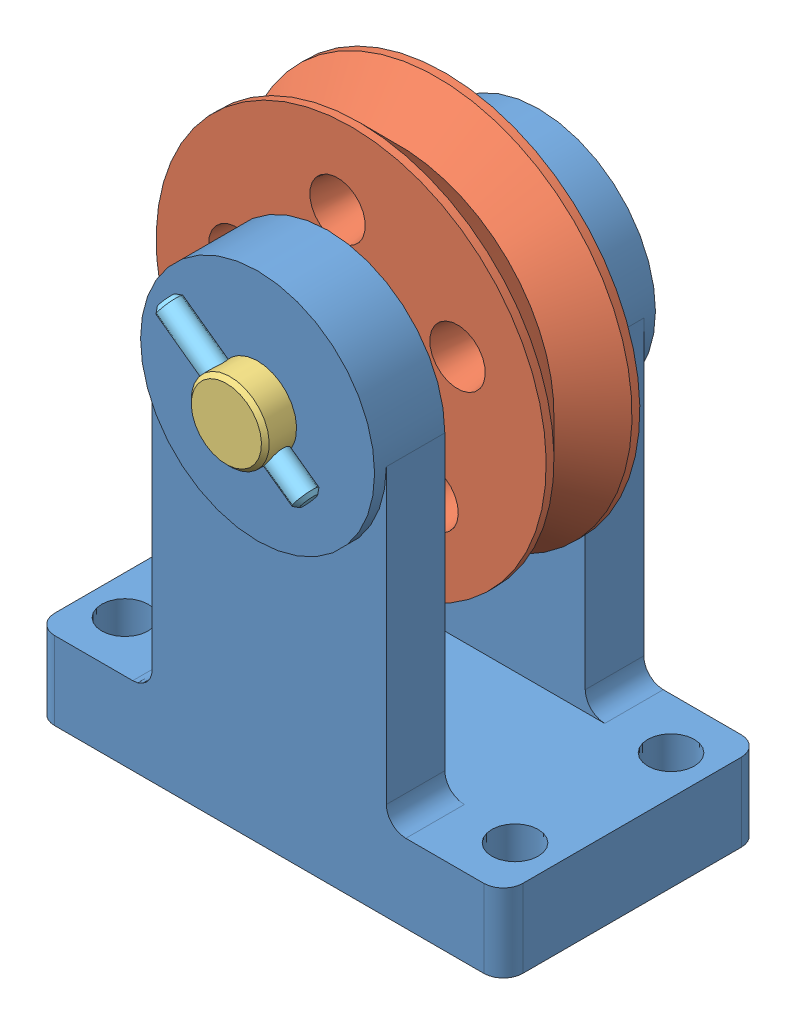
SolidWorks assembly PARCA_BİRLESTIRMESI, configuration Varsayılan. Lengths in mm.
Overall size (136.15 168.07 87).
5 component instances, 5 part files, 8 mates.
Components (placement in the parent):
- kasnak_yeri-1: kasnak_yeri [Default] at (-26.8186 -62.4075 130) size (120 130 72)
- kasnak-1: kasnak [Default] at (-26.8186 37.5925 130) x (-0.872021 0.489469 0) z (0 0 1) size (100 100 30)
- pım-2: pım [Default] at (-26.8186 37.5925 87) x (0 0 1) z (-0.585701 -0.810527 0) size (87 40 40)
- silindir-1: silindir [Default] at (-26.9474 37.6161 115) x (0.952713 0.303871 0) z (0 0 1) size (30 30 30)
- tıkac-1: tıkac [Default] at (-47.2136 52.3303 169) x (-0.810527 0.585701 0) z (0 0 1) size (45 6 6)
Mates (geometry in assembly coordinates):
- Concentric1: concentric aligned: cylinder of kasnak_yeri-1 through (-26.8186 37.5925 145) axis (0 0 1) radius 20; cylinder of kasnak-1 through (-26.8186 37.5925 164.8851) axis (0 0 1) radius 20
- Coincident3: coincident anti-aligned: plane of kasnak_yeri-1 through (-26.8186 37.5925 94) normal (0 0 -1); circle of pım-2
- Coincident5: coincident aligned: plane of kasnak-1 through (-36.6079 20.152 145) normal (0 0 1); plane of silindir-1 through (-26.9474 37.6161 145) normal (0 0 1)
- Lock1: lock: unknown of kasnak-1; unknown of silindir-1
- Concentric5: concentric aligned: cylinder of pım-2 through (13.7078 8.3074 169) axis (-0.810527 0.585701 0) radius 3; cylinder of tıkac-1 through (-28.9767 39.152 169) axis (-0.810527 0.585701 0) radius 3
- Lock4: lock: unknown of pım-2; unknown of tıkac-1
- Concentric7: concentric aligned: cylinder of kasnak_yeri-1 through (-26.8186 37.5925 97) axis (0 0 1) radius 10; cylinder of pım-2 through (-26.8186 37.5925 65.7157) axis (0 0 1) radius 10
- Coincident9: coincident anti-aligned: plane of kasnak_yeri-1 through (-26.8186 37.5925 145) normal (0 0 -1); plane of kasnak-1 through (-36.6079 20.152 145) normal (0 0 1)
